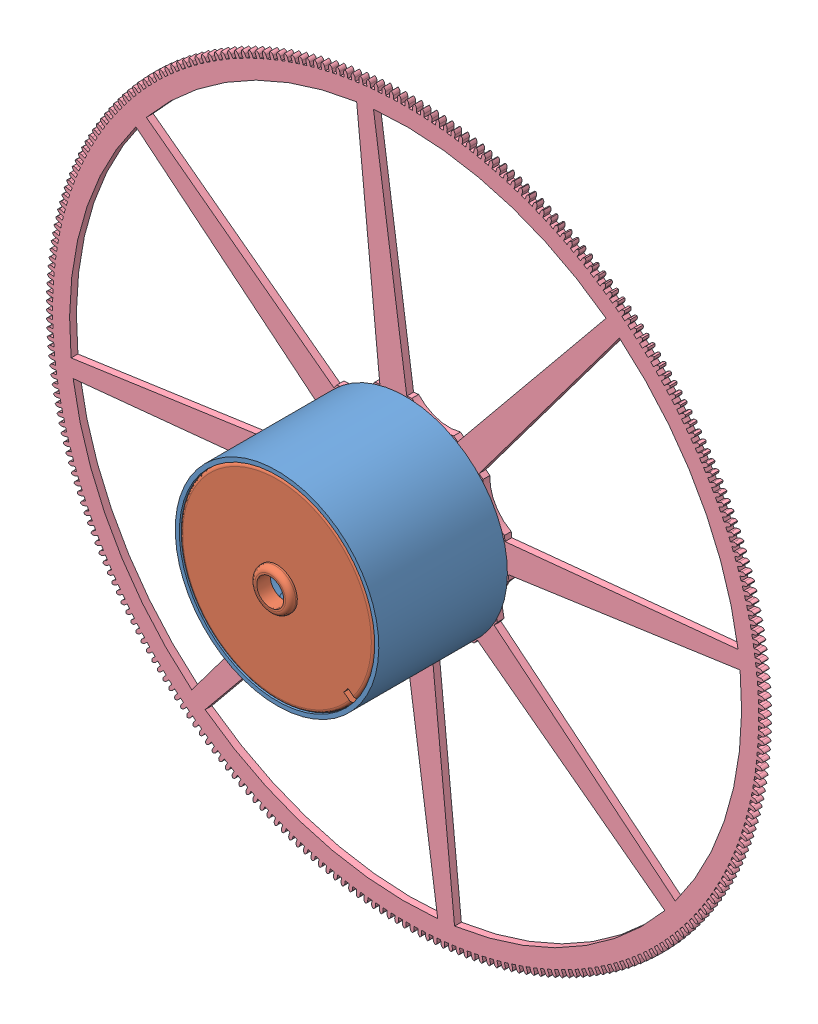
SolidWorks assembly barrel assy, configuration Default. Lengths in mm.
Overall size (297.48 297.48 41.9).
4 component instances, 4 part files, 9 mates.
Components (placement in the parent):
- barrel-1: barrel [Default] at (-66.9035 -193.9176 -9.3) x (-0.787259 0.616622 0) z (0 0 1) size (60 60 37.9)
- barrel front cap-1: barrel front cap [Default] at (-66.9035 -193.9176 -9.3) x (-0.787259 0.616622 0) z (0 0 1) size (57.64 57.6 4.06)
- barrel rear cap-1: barrel rear cap [Default] at (-66.9035 -193.9176 -51.2) x (0.787259 -0.616622 0) z (0 0 -1) size (57.6 57.6 4)
- great wheel-1: great wheel [Default] at (85.4176 -175.4035 -49.2) x (-0.616622 -0.787259 0) z (0 0 1) size (211.89 211.9 2)
Mates (geometry in assembly coordinates):
- Concentric1: concentric: cylinder of barrel-1 through (0 -108.5 -49.2) axis (0 0 1) radius 27.5; circle of barrel front cap-1
- Coincident1: coincident: plane of barrel-1 through (0 -108.5 -13.3) normal (0 0 1); plane of barrel front cap-1 through (0 -108.5 -13.3) normal (0 0 -1)
- Parallel1: parallel: plane of barrel-1 through (-66.9035 -193.9176 -9.3) normal (-0.616622 -0.787259 0); plane of barrel front cap-1 through (-66.9035 -193.9176 -9.3) normal (-0.616622 -0.787259 0)
- Coincident2: coincident: plane of barrel-1 through (0 -108.5 -47.2) normal (0 0 -1); plane of barrel rear cap-1 through (0 -108.5 -47.2) normal (0 0 1)
- Concentric2: concentric: cylinder of barrel-1 through (0 -108.5 -47.2) axis (0 0 -1) radius 28.8; cylinder of barrel rear cap-1 through (0 -108.5 -47.2) axis (0 0 -1) radius 28.8
- Parallel2: parallel: plane of barrel-1 through (-66.9035 -193.9176 -9.3) normal (-0.616622 -0.787259 0); plane of barrel rear cap-1 through (-66.9035 -193.9176 -51.2) normal (-0.616622 -0.787259 0)
- Coincident3: coincident: plane of barrel rear cap-1 through (0 -108.5 -49.2) normal (0 0 -1); plane of great wheel-1 through (0 -108.5 -49.2) normal (0 0 1)
- Concentric3: concentric: circle of barrel rear cap-1; circle of great wheel-1
- Concentric6: concentric: cylinder of barrel rear cap-1 through (-2.2925 -89.6388 -49.2) axis (0 0 -1) radius 1.25; circle of great wheel-1
